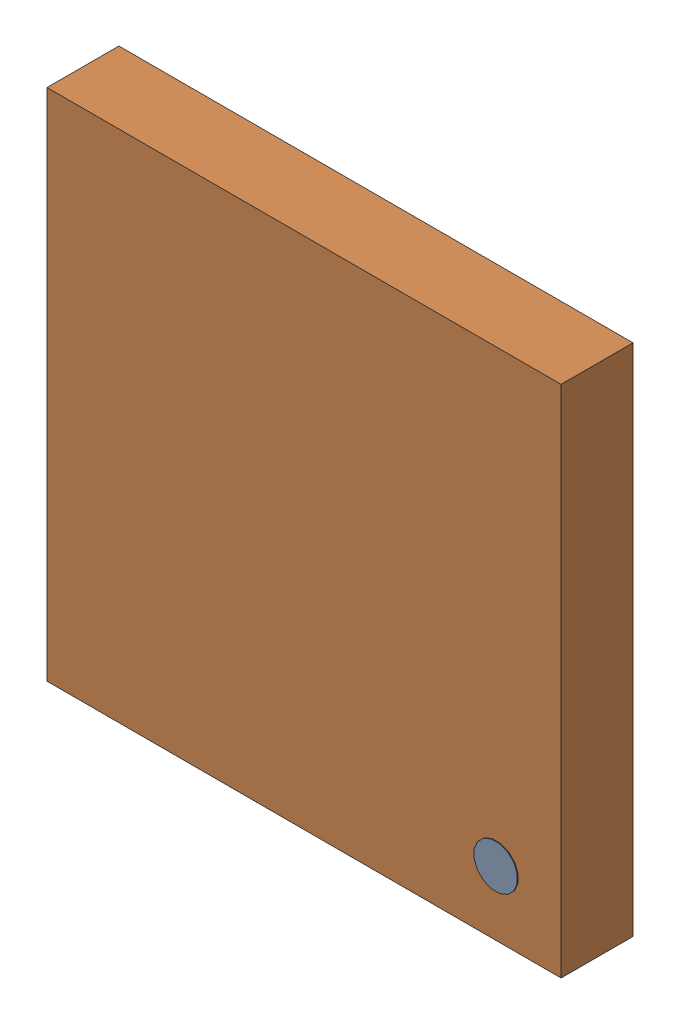
SolidWorks assembly U1, configuration Default. Lengths in mm.
Overall size (7.15 7.15 1.01).
4 component instances, 2 part files, 0 mates.
Components (placement in the parent):
- 6575497872-1: 6575497872 [Default] at (30.615 17.645 0.5) size (0.6 0.6 0.51)
  - Extruded_4-1: Extruded_4 [Default] at origin size (0.6 0.6 0.51)
- 6575497792-1: 6575497792 [Default] at (27.94 20.32 0) size (7.15 7.15 1)
  - Extruded_5-1: Extruded_5 [Default] at origin size (7.15 7.15 1)
